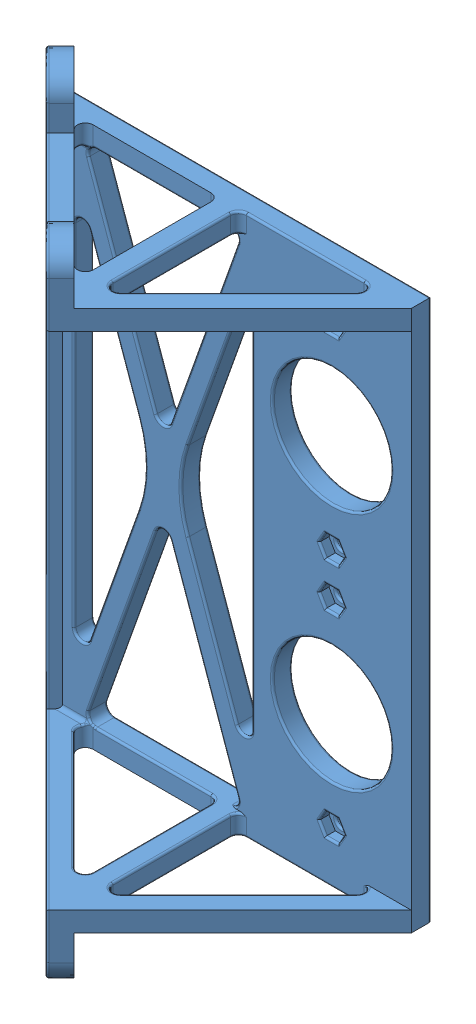
SolidWorks assembly Pump Rack Reference Assembly, configuration Default. Lengths in mm.
Overall size (93.47 162.6 50.9).
3 component instances, 2 part files, 8 mates.
Components (placement in the parent):
- Pump-1: Pump [Default] at origin size (54.7 55.8 65.4) (hidden)
- Pump Rack-2: Pump Rack [Default] at origin size (93.47 162.6 50.9)
- Pump-2: Pump [Default] at (0 60.8 0) size (54.7 55.8 65.4) (hidden)
Mates (geometry in assembly coordinates):
- Coincident1: coordinate: unknown of Pump-1
- InPlace1: in place: plane of ? through (18.1 8.0998 0) normal (0 0 1); plane of ? through (0 0 0) normal (0 0 1); moOrthogonalPlaneRef_w of ? through (18.1 8.0998 0) normal (0 0 1); plane of ? through (0 0 0) normal (0 1 0); plane of ? through (18.1 8.0998 0) normal (0 0 1); plane of ? through (0 0 0) normal (1 0 0); plane of ? through (18.1 8.0998 0) normal (0 0 1); unknown of ?
- Coincident2: coincident aligned: plane of Pump-1; plane of Pump Rack-2
- Coincident3: coincident aligned: moOrthogonalPlaneRef_w of Pump-1 through (0 0 0) normal (0 1 0); plane of Pump Rack-2 through (0 0 0) normal (0 1 0)
- Coincident4: coincident anti-aligned: moOrthogonalPlaneRef_w of Pump-1 through (0 0 0) normal (-1 0 0); plane of Pump Rack-2 through (0 0 0) normal (1 0 0)
- Coincident2: coincident anti-aligned: plane of Pump Rack-2 through (0 0 0) normal (0 0 -1); plane of Pump-2 through (18.1 68.8998 0) normal (0 0 1)
- Concentric1: concentric anti-aligned: cylinder of Pump Rack-2 through (0 85.7 5) axis (0 0 -1) radius 1.5; cylinder of Pump-2 through (0 85.7 -3) axis (0 0 1) radius 1.5
- Concentric2: concentric anti-aligned: cylinder of Pump Rack-2 through (0 35.9 5) axis (0 0 -1) radius 1.5; cylinder of Pump-2 through (0 35.9 -3) axis (0 0 1) radius 1.5
